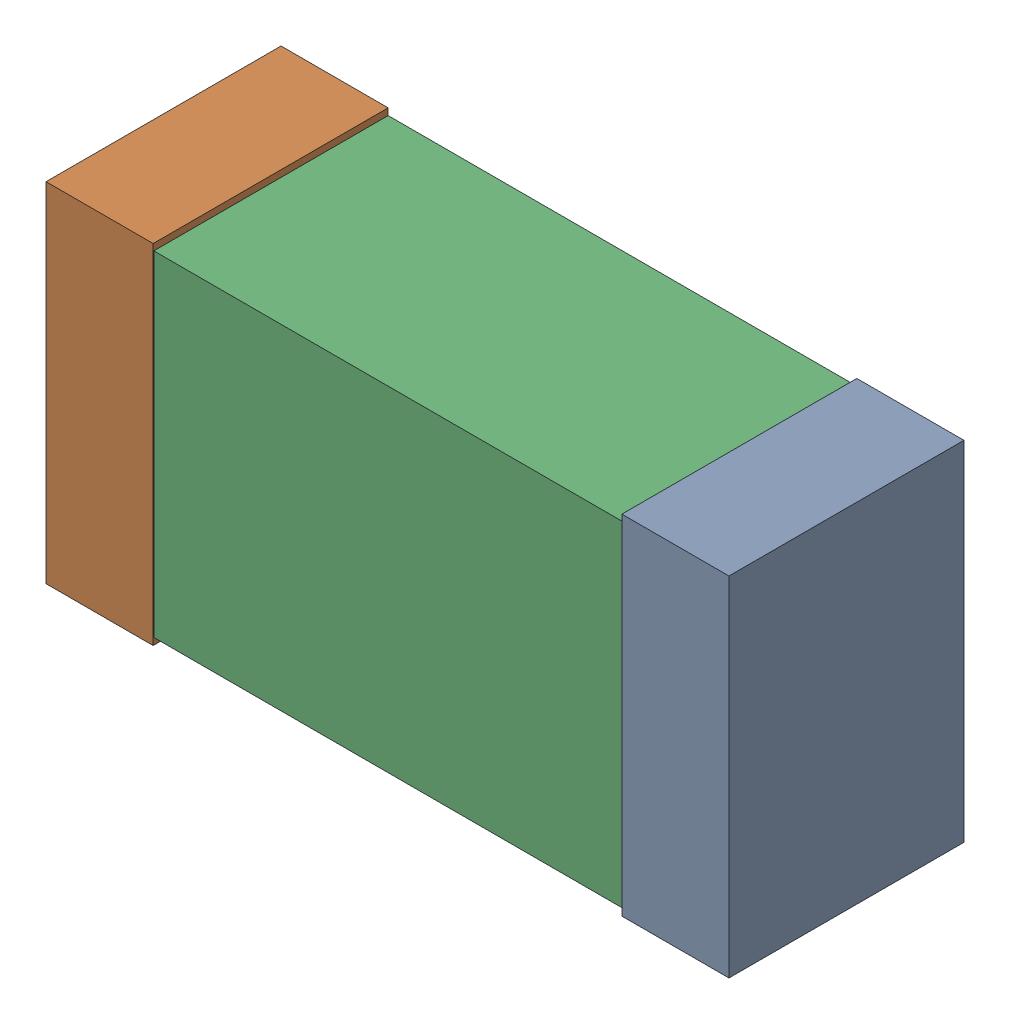
SolidWorks assembly R9, configuration Default. Lengths in mm.
Overall size (1.02 0.52 0.35).
6 component instances, 2 part files, 0 mates.
Components (placement in the parent):
- 870940480-1: 870940480 [Default] at (55.2678 27.4552 0) size (0.16 0.52 0.35)
  - Extruded-1: Extruded [Default] at origin size (0.16 0.52 0.35)
- 870940480-2: 870940480 [Default] at (54.4078 27.4552 0) size (0.16 0.52 0.35)
  - Extruded-1: Extruded [Default] at origin size (0.16 0.52 0.35)
- 870940640-1: 870940640 [Default] at (54.8378 27.4552 0) size (1 0.5 0.35)
  - Extruded_2-1: Extruded_2 [Default] at origin size (1 0.5 0.35)
